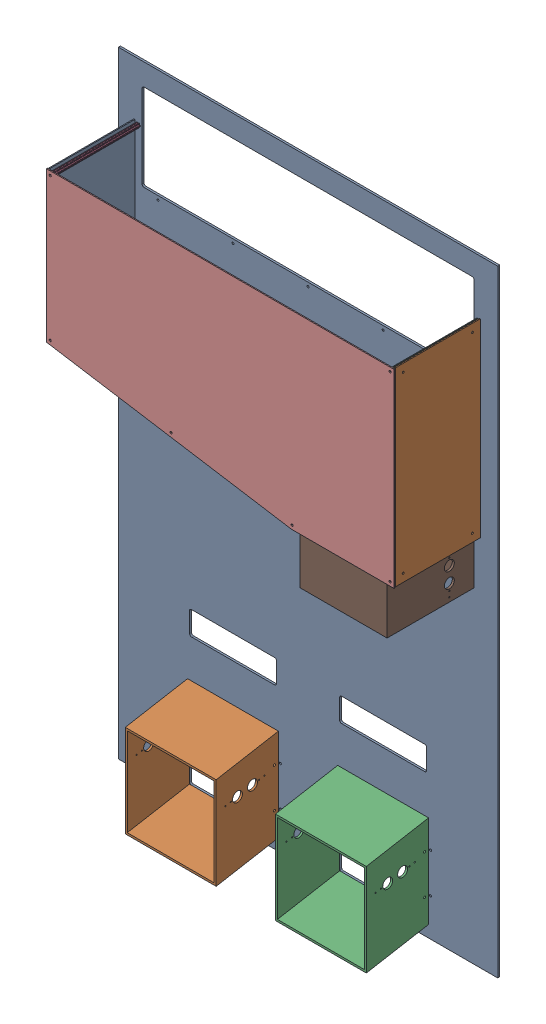
SolidWorks assembly GE-16097_ASM, configuration Default. Lengths in mm.
Overall size (1219.2 1981.2 288.93).
14 component instances, 8 part files, 0 mates.
Components (placement in the parent):
- GE-16098-1: GE-16098 [Default] at origin size (1219.2 1981.2 6.35)
- GE-16099-1: GE-16099 [Default] at (-241.3 -987.8833 206.4629) x (1 0 0) z (0 -1 0) size (292.1 200.11 331.89)
- GE-16099-2: GE-16099 [Default] at (241.3 -987.8833 206.4629) x (1 0 0) z (0 -1 0) size (292.1 200.11 331.89)
- GE-16100-1: GE-16100 [Default] at (-546.1 806.45 6.35) size (14.66 12.7 279.4)
- GE-16100-2: GE-16100 [Default] at (-546.1 347.3657 6.35) size (14.66 12.7 279.4)
- GE-16100-3: GE-16100 [Default] at (-157.4232 284.6759 6.35) size (14.66 12.7 279.4)
- GE-16100-4: GE-16100 [Default] at (231.2537 221.9861 6.35) size (14.66 12.7 279.4)
- GE-16100-5: GE-16100 [Default] at (546.1 222.25 6.35) size (14.66 12.7 279.4)
- GE-16100-6: GE-16100 [Default] at (546.1 806.45 6.35) size (14.66 12.7 279.4)
- GE-16101-1: GE-16101 [Default] at (-558.8 819.15 285.75) size (1117.6 609.6 3.17)
- GE-16102-1: GE-16102 [Default] at (393.7 209.55 285.75) size (279.4 152.4 279.4)
- GE-16103-1: GE-16103 [Default] at (-552.45 354.822 9.525) x (0.987241 -0.159232 0) z (0 0 1) size (800.1 3.17 273.05)
- GE-16104-1: GE-16104 [Default] at (-556.6073 336.55 282.575) size (3.17 482.6 273.05)
- GE-16105-1: GE-16105 [Default] at (553.4323 209.55 282.575) size (3.17 609.6 273.05)
